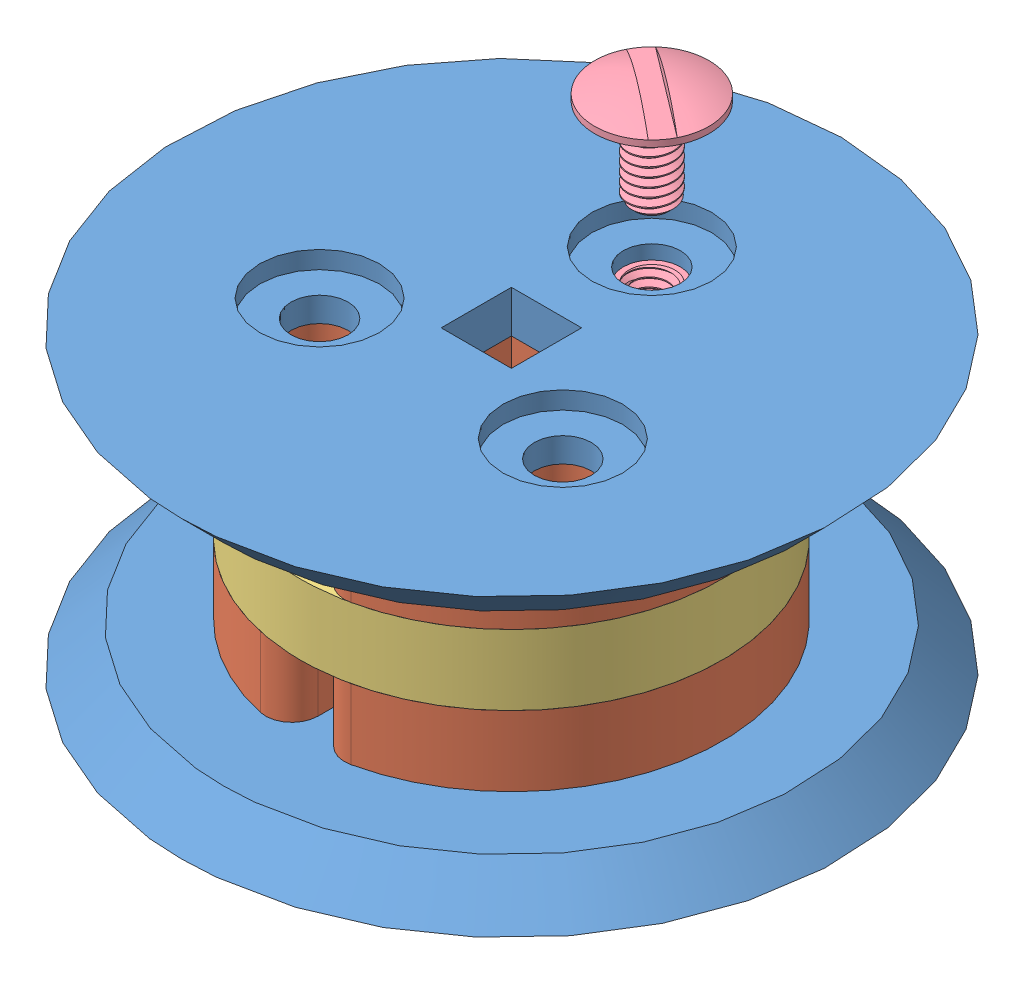
SolidWorks assembly screw compound pulley, configuration Default. Lengths in mm.
Overall size (63.5 39.66 63.5).
6 component instances, 4 part files, 14 mates.
Components (placement in the parent):
- pulley guide-1: pulley guide [Default] at (14.7507 32.2262 49.2245) size (63.5 3.81 63.5)
- slot pulley-1: slot pulley [Default] at (14.7507 36.0362 49.2245) size (38.1 6.35 37.71)
- hole pulley-1: hole pulley [Default] at (14.7507 42.3862 49.2245) size (38.1 6.35 38.1)
- slot pulley-2: slot pulley [Default] at (14.7507 48.7362 49.2245) size (38.1 6.35 37.71)
- pulley guide-2: pulley guide [Default] at (14.7507 58.8962 49.2245) x (-1 0 0) z (0 0 1) size (63.5 3.81 63.5)
- 93813A342_BRASS LOW-PROFILE BINDING POST-1: 93813A342_BRASS LOW-PROFILE BINDING POST [93813A342] at (14.7507 62.3887 36.5245) x (0 1 0) z (0.797408 0 0.60344) size (39.66 10.32 10.32)
Mates (geometry in assembly coordinates):
- Concentric1: concentric aligned: cylinder of pulley guide-1 through (14.7507 36.0362 36.5245) axis (0 -1 0) radius 2.5797; cylinder of slot pulley-1 through (14.7507 42.3862 36.5245) axis (0 -1 0) radius 2.5797
- Concentric2: concentric aligned: cylinder of pulley guide-1 through (3.7521 36.0362 55.5745) axis (0 -1 0) radius 2.5797; cylinder of slot pulley-1 through (3.7521 42.3862 55.5745) axis (0 -1 0) radius 2.5797
- Concentric3: concentric aligned: cylinder of slot pulley-1 through (14.7507 42.3862 36.5245) axis (0 -1 0) radius 2.5797; cylinder of hole pulley-1 through (14.7507 48.7362 36.5245) axis (0 -1 0) radius 2.5797
- Coincident1: coincident anti-aligned: plane of pulley guide-1 through (14.7507 36.0362 49.2245) normal (0 1 0); plane of slot pulley-1 through (14.7507 36.0362 60.1279) normal (0 -1 0)
- Coincident2: coincident anti-aligned: plane of slot pulley-1 through (14.7507 42.3862 60.1279) normal (0 1 0); plane of hole pulley-1 through (14.7507 42.3862 49.2245) normal (0 -1 0)
- Concentric4: concentric aligned: cylinder of slot pulley-1 through (25.7492 42.3862 55.5745) axis (0 -1 0) radius 2.5797; cylinder of hole pulley-1 through (25.7492 48.7362 55.5745) axis (0 -1 0) radius 2.5797
- Coincident3: coincident anti-aligned: plane of hole pulley-1 through (14.7507 48.7362 49.2245) normal (0 1 0); plane of slot pulley-2 through (14.7507 48.7362 60.1279) normal (0 -1 0)
- Concentric5: concentric aligned: cylinder of hole pulley-1 through (14.7507 48.7362 36.5245) axis (0 -1 0) radius 2.5797; cylinder of slot pulley-2 through (14.7507 55.0862 36.5245) axis (0 -1 0) radius 2.5797
- Concentric6: concentric aligned: cylinder of hole pulley-1 through (3.7521 48.7362 55.5745) axis (0 -1 0) radius 2.5797; cylinder of slot pulley-2 through (3.7521 55.0862 55.5745) axis (0 -1 0) radius 2.5797
- Coincident41: coincident anti-aligned: plane of slot pulley-2 through (14.7507 55.0862 60.1279) normal (0 1 0); plane of pulley guide-2 through (14.7507 55.0862 49.2245) normal (0 -1 0)
- Concentric7: concentric anti-aligned: cylinder of slot pulley-2 through (14.7507 55.0862 36.5245) axis (0 -1 0) radius 2.5797; cylinder of pulley guide-2 through (14.7507 55.0862 36.5245) axis (0 1 0) radius 2.5797
- Concentric8: concentric anti-aligned: cylinder of slot pulley-2 through (3.7521 55.0862 55.5745) axis (0 -1 0) radius 2.5797; cylinder of pulley guide-2 through (3.7521 55.0862 55.5745) axis (0 1 0) radius 2.5797
- Concentric9: concentric anti-aligned: cylinder of pulley guide-1 through (14.7507 36.0362 36.5245) axis (0 -1 0) radius 2.5797; cylinder of 93813A342_BRASS LOW-PROFILE BINDING POST-1 through (14.7507 46.5137 36.5245) axis (0 1 0) radius 2.5797
- Coincident8: coincident anti-aligned: plane of pulley guide-1 through (14.7507 33.8137 36.5245) normal (0 -1 0); plane of 93813A342_BRASS LOW-PROFILE BINDING POST-1 through (14.7507 33.8137 36.5245) normal (0 1 0)
